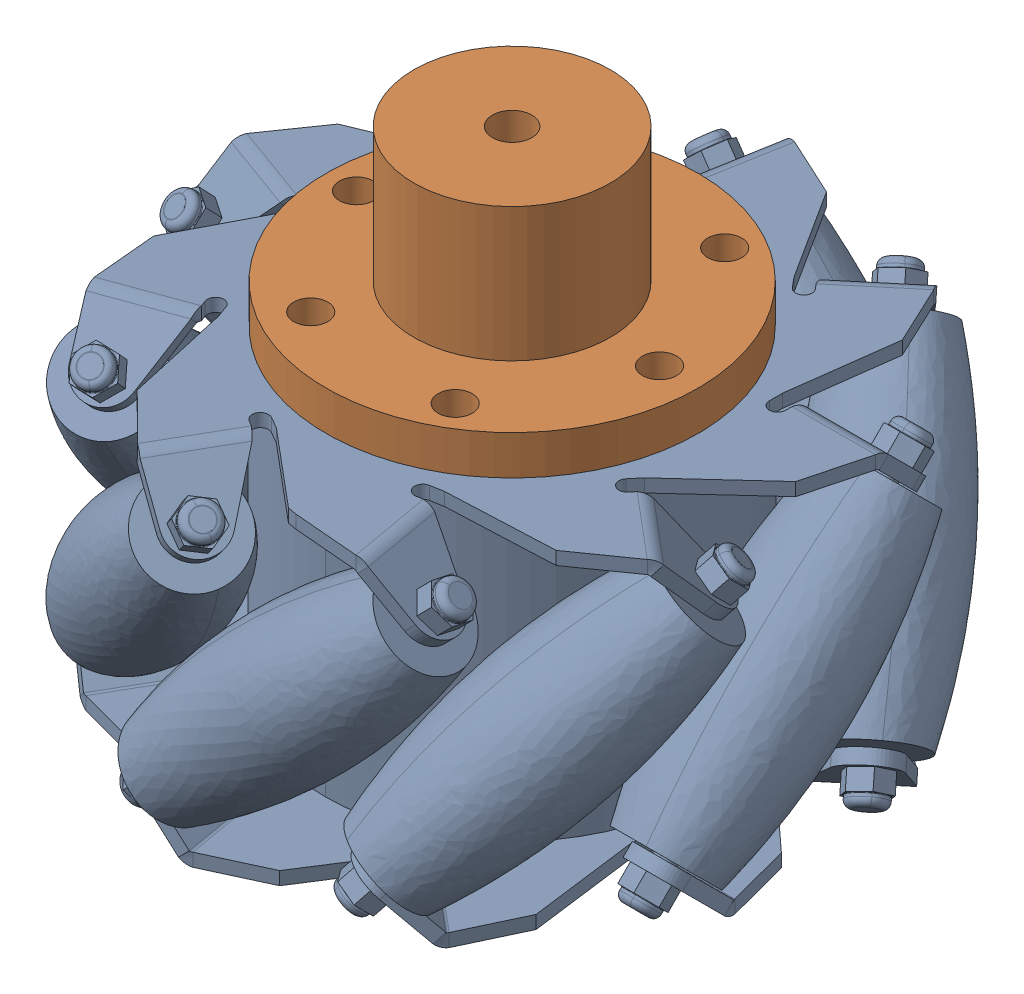
SolidWorks assembly 100mm_LB, configuration 默认. Lengths in mm.
Overall size (102.05 76.39 102.38).
2 component instances, 2 part files, 4 mates.
Components (placement in the parent):
- 100mm_LB-1: 100mm_LB [默认] at origin size (102.05 50.01 102.38)
- 6mm_TightCoupling-1: 6mm_TightCoupling [默认] at (0 47.9113 0) x (0.5 0 0.866025) z (0 1 0) size (56.8 56.8 26.4)
Mates (geometry in assembly coordinates):
- 同心1: concentric: cylinder of 100mm_LB-1 through (11.875 -2.0707 -20.5681) axis (0 1 0) radius 2.5; cylinder of 6mm_TightCoupling-1 through (11.875 47.9113 -20.5681) axis (0 1 0) radius 2.6
- 同心2: concentric: cylinder of 100mm_LB-1 through (11.875 -2.0707 20.5681) axis (0 1 0) radius 2.5; cylinder of 6mm_TightCoupling-1 through (11.875 47.9113 20.5681) axis (0 1 0) radius 2.6
- 同心3: concentric: cylinder of 100mm_LB-1 through (-23.75 -2.0707 0) axis (0 1 0) radius 2.5; cylinder of 6mm_TightCoupling-1 through (-23.75 47.9113 0) axis (0 1 0) radius 2.6
- 重合1: coincident anti-aligned: plane of 100mm_LB-1 through (0 47.9113 0) normal (0 1 0); plane of 6mm_TightCoupling-1 through (-3.8049 47.9113 -6.5902) normal (0 -1 0)
